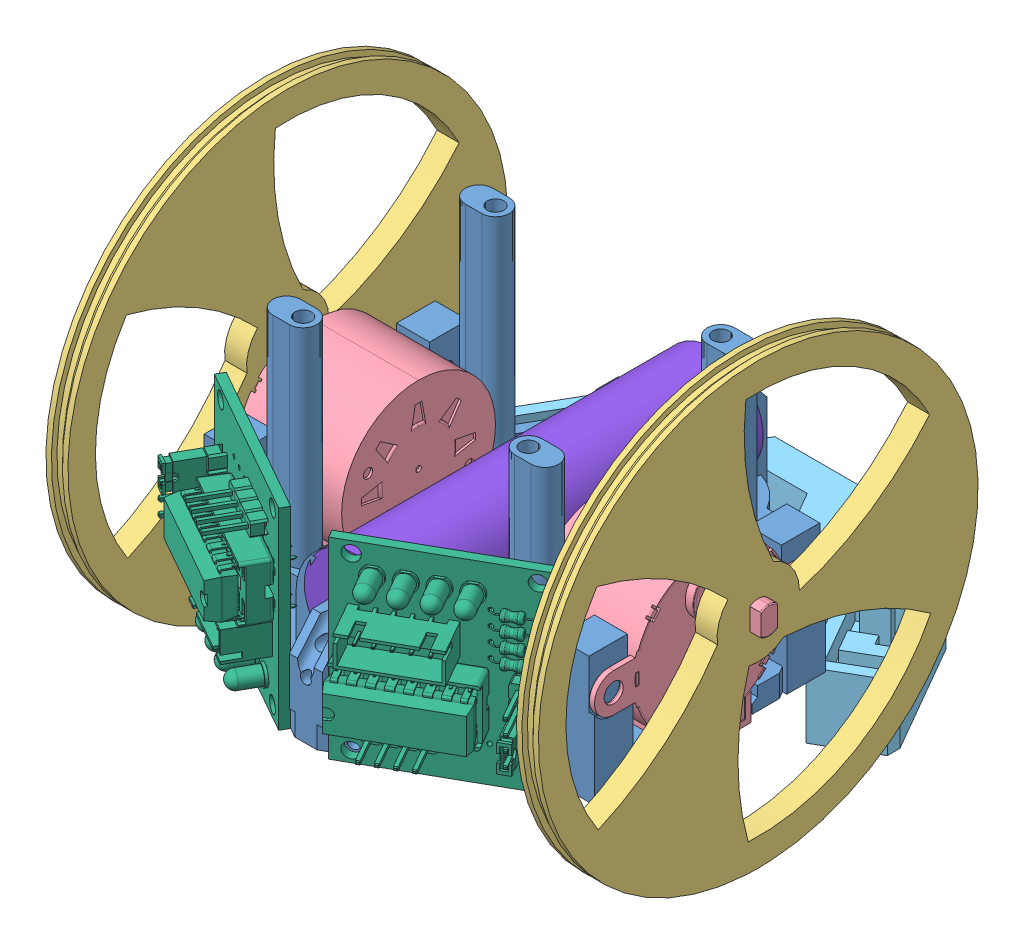
SolidWorks assembly Assem1, configuration Default. Lengths in mm.
Overall size (93.61 80 101.68).
12 component instances, 9 part files, 38 mates.
Components (placement in the parent):
- base-1: base [Default] at origin size (72 47 81.69)
- sarhoş-1: sarhoş [Default] at (0 0 -32.5) size (22.2 15 16.2)
- tkr-1: tkr [Default] at (40.8 24 0) x (1 0 0) z (0 1 0) size (4 80 80)
- 28byj-48 5v stepper motor-2: 28byj-48 5v stepper motor [Default] at (-36 16 0) x (0 0 1) z (0 -1 0) size (42 29.81 31)
- tkr-2: tkr [Default] at (-44.8 24 0) x (1 0 0) z (0 1 0) size (4 80 80)
- basup2-1: basup2 [Default] at (0 49.6577 9.7533) size (72 2 85) (hidden)
- 28byj-48 5v stepper motor-3: 28byj-48 5v stepper motor [Default] at (36 16 0) x (0 0 -1) z (0 -1 0) size (42 29.81 31)
- sarz_unit-1: sarz_unit [Default] at (0 -16 -41.5) size (77.62 14 31.45)
- ULN2003 Stepper Driver-1: ULN2003 Stepper Driver [Default] at (17.2497 17.5 28.8761) x (-0.870452 0 0.492254) z (0.492254 0 0.870452) size (31 35 12.67)
- +++ ESP8266 NodeMCU Board +++-1: +++ ESP8266 NodeMCU Board +++ [Default] at (0 6.65 0.5) x (-1 0 0) z (0 0 1) size (25.69 12.43 48.54)
- pil2-2: pil2 [Default] at (-0.2449 15.9 28.3) x (-0.73112 -0.682249 0) z (0.682249 -0.73112 0) size (18.5 65 18.5)
- ULN2003 Stepper Driver-2: ULN2003 Stepper Driver [Default] at (-17.2497 17.5 28.8761) x (0.870452 0 0.492254) z (-0.492254 0 0.870452) size (31 35 12.67)
Mates (geometry in assembly coordinates):
- Coincident1: coincident aligned: plane of base-1 through (0 0 0) normal (0 1 0)
- Coincident2: coincident aligned: plane of base-1 through (0 0 0) normal (1 0 0)
- Coincident3: coincident aligned: plane of base-1 through (0 0 0) normal (0 0 1)
- Width8: width aligned: plane of basup2-1 through (36 51.6577 39.7533) normal (1 0 0); plane of basup2-1 through (-36 51.6577 39.7533) normal (-1 0 0); plane of base-1 through (36 23 14) normal (1 0 0); plane of base-1 through (-36 23 14) normal (-1 0 0)
- Width9: width aligned: plane of basup2-1 through (36 51.6577 39.7533) normal (1 0 0); plane of base-1 through (-36 51.6577 39.7533) normal (-1 0 0); plane of basup2-1 through (36 4 -12.6462) normal (1 0 0); plane of base-1 through (-36 4 -12.6462) normal (-1 0 0)
- Coincident20: coincident anti-aligned: plane of base-1 through (0 0 -32.5) normal (0 -1 0); plane of sarhoş-1 through (-4.05 0 -32.5) normal (0 1 0)
- Width10: width aligned: plane of 28byj-48 5v stepper motor-2 through (-19 -1 7.3) normal (0 0 1); plane of 28byj-48 5v stepper motor-2 through (-19 4.0539 -7.3) normal (0 0 -1); plane of base-1 through (-36 -6 -7.7) normal (0 0 1); plane of base-1 through (-36 -6 7.7) normal (0 0 -1)
- Coincident21: coincident anti-aligned: plane of base-1 through (-35 16 -18) normal (-1 0 0); plane of 28byj-48 5v stepper motor-2 through (-35 16 -17.5) normal (1 0 0)
- Coincident22: coincident anti-aligned: plane of base-1 through (-35 12.5 -14) normal (0 1 0); plane of 28byj-48 5v stepper motor-2 through (-35 12.5 -13.5554) normal (0 -1 0)
- Width11: width anti-aligned: plane of 28byj-48 5v stepper motor-3 through (19 4.0539 7.3) normal (0 0 1); plane of 28byj-48 5v stepper motor-3 through (19 -1 -7.3) normal (0 0 -1); plane of base-1 through (36 -6 7.7) normal (0 0 -1); plane of base-1 through (36 -6 -7.7) normal (0 0 1)
- Coincident23: coincident anti-aligned: plane of base-1 through (35 16 18) normal (1 0 0); plane of 28byj-48 5v stepper motor-3 through (35 16 17.5) normal (-1 0 0)
- Coincident24: coincident anti-aligned: plane of base-1 through (35 12.5 14) normal (0 1 0); plane of 28byj-48 5v stepper motor-3 through (35 12.5 13.5554) normal (0 -1 0)
- Concentric11: concentric anti-aligned: cylinder of 28byj-48 5v stepper motor-2 through (-40.8 24 0) axis (1 0 0) radius 2.5; cylinder of tkr-2 through (-40.8 24 0) axis (-1 0 0) radius 2.5
- Coincident25: coincident anti-aligned: plane of 28byj-48 5v stepper motor-2 through (-46.8 26 1.5) normal (0 0 1); plane of tkr-2 through (-40.8 22 1.5) normal (0 0 -1)
- Coincident26: coincident anti-aligned: plane of 28byj-48 5v stepper motor-2 through (-40.8 24 0) normal (-1 0 0); plane of tkr-2 through (-40.8 24 0) normal (1 0 0)
- Concentric12: concentric aligned: cylinder of tkr-1 through (44.8 24 0) axis (-1 0 0) radius 2.5; cylinder of 28byj-48 5v stepper motor-3 through (40.8 24 0) axis (-1 0 0) radius 2.5
- Coincident27: coincident anti-aligned: plane of tkr-1 through (44.8 22 1.5) normal (0 0 -1); plane of 28byj-48 5v stepper motor-3 through (46.8 26 1.5) normal (0 0 1)
- Coincident28: coincident anti-aligned: plane of tkr-1 through (40.8 24 0) normal (-1 0 0); plane of 28byj-48 5v stepper motor-3 through (40.8 24 0) normal (1 0 0)
- Distance2: distance = 20 mm anti-aligned: plane of base-1 through (0 4 -32.5) normal (0 1 0); plane of sarz_unit-1 through (0 -16 -41.5) normal (0 -1 0)
- Parallel5: parallel anti-aligned: plane of base-1 through (21.6506 4 -37.5) normal (0 0 -1); plane of sarz_unit-1 through (-21.65 -2 -41.5) normal (0 0 1)
- Width12: width aligned: plane of sarz_unit-1 through (-38.8103 -4 -31.7776) normal (-1 0 0); plane of base-1 through (38.8103 -4 -31.7776) normal (1 0 0); plane of sarz_unit-1 through (-36 4 -12.6462) normal (-1 0 0); plane of base-1 through (36 4 -12.6462) normal (1 0 0)
- Parallel11: parallel aligned: plane of base-1 through (0 4 -32.5) normal (0 1 0); plane of +++ ESP8266 NodeMCU Board +++-1 through (0 6.65 0.5) normal (0 1 0)
- Width15: width anti-aligned: plane of base-1 through (-36 23 14) normal (-1 0 0); plane of +++ ESP8266 NodeMCU Board +++-1 through (36 23 14) normal (1 0 0); plane of base-1 through (12.845 6.65 -21.575) normal (1 0 0); plane of +++ ESP8266 NodeMCU Board +++-1 through (-12.845 6.65 22.575) normal (-1 0 0)
- Width16: width anti-aligned: plane of +++ ESP8266 NodeMCU Board +++-1 through (10.845 6.65 24.575) normal (0 0 1); plane of base-1 through (-10.845 6.65 -23.575) normal (0 0 -1); plane of +++ ESP8266 NodeMCU Board +++-1 through (5 2 24.5) normal (0 0 -1); plane of base-1 through (-13 2 -23.5) normal (0 0 1)
- Width17: width anti-aligned: plane of +++ ESP8266 NodeMCU Board +++-1 through (12.845 6.65 -21.575) normal (1 0 0); plane of base-1 through (-12.845 6.65 22.575) normal (-1 0 0); plane of +++ ESP8266 NodeMCU Board +++-1 through (13 2 24.5) normal (-1 0 0); plane of base-1 through (-13 2 24.5) normal (1 0 0)
- Coincident32: coincident anti-aligned: plane of base-1 through (10.5 5 -21) normal (0 1 0); plane of +++ ESP8266 NodeMCU Board +++-1 through (0 5 0.5) normal (0 -1 0)
- Coincident33: coincident anti-aligned: plane of base-1 through (-3 15 -36.7) normal (0 0 1); plane of pil2-2 through (-0.2449 15.9 -36.7) normal (0 0 -1)
- Tangent1: tangent aligned: cylinder of base-1 through (0 15.85 -27.7) axis (0 0 1) radius 9; cylinder of pil2-2 through (-0.2449 15.9 -36.7) axis (0 0 1) radius 9.25
- Tangent2: tangent anti-aligned: plane of +++ ESP8266 NodeMCU Board +++-1 through (0 6.65 0.5) normal (0 1 0); cylinder of pil2-2 through (-0.2449 15.9 -36.7) axis (0 0 1) radius 9.25
- Concentric13: concentric anti-aligned: cylinder of base-1 through (-8.1 4 -32.5) axis (0 -1 0) radius 1.5; cylinder of sarhoş-1 through (-8.1 -8 -32.5) axis (0 1 0) radius 3
- Concentric14: concentric anti-aligned: cylinder of base-1 through (8.1 4 -32.5) axis (0 -1 0) radius 1.5; cylinder of sarhoş-1 through (8.1 -8 -32.5) axis (0 1 0) radius 3
- Distance3: distance = 4 mm: plane of base-1 through (21.6506 4 -37.5) normal (0 0 -1); line of sarz_unit-1 through (8.8453 -2 -41.5) axis (0 -1 0)
- Coincident34: coincident aligned: plane of base-1 through (0 0 -32.5) normal (0 -1 0); plane of ULN2003 Stepper Driver-1 through (3.7577 0 36.506) normal (0 -1 0)
- Coincident35: coincident anti-aligned: plane of base-1 through (31.1769 -6 21) normal (0.492254 0 0.870452); plane of ULN2003 Stepper Driver-1 through (17.2497 17.5 28.8761) normal (-0.492254 0 -0.870452)
- Concentric15: concentric aligned: cylinder of base-1 through (26.1613 2 19.2411) axis (0.492254 0 0.870452) radius 1; cylinder of ULN2003 Stepper Driver-1 through (28.1303 2 22.7229) axis (0.492254 0 0.870452) radius 1.375
- Coincident37: coincident anti-aligned: plane of base-1 through (-31.1769 -6 21) normal (-0.492254 0 0.870452); plane of ULN2003 Stepper Driver-2 through (-17.2497 17.5 28.8761) normal (0.492254 0 -0.870452)
- Coincident38: coincident aligned: plane of base-1 through (0 0 -32.5) normal (0 -1 0); plane of ULN2003 Stepper Driver-2 through (-30.7417 0 21.2461) normal (0 -1 0)
- Concentric17: concentric aligned: cylinder of base-1 through (-26.1613 2 19.2411) axis (-0.492254 0 0.870452) radius 1; cylinder of ULN2003 Stepper Driver-2 through (-28.1303 2 22.7229) axis (-0.492254 0 0.870452) radius 1.375
